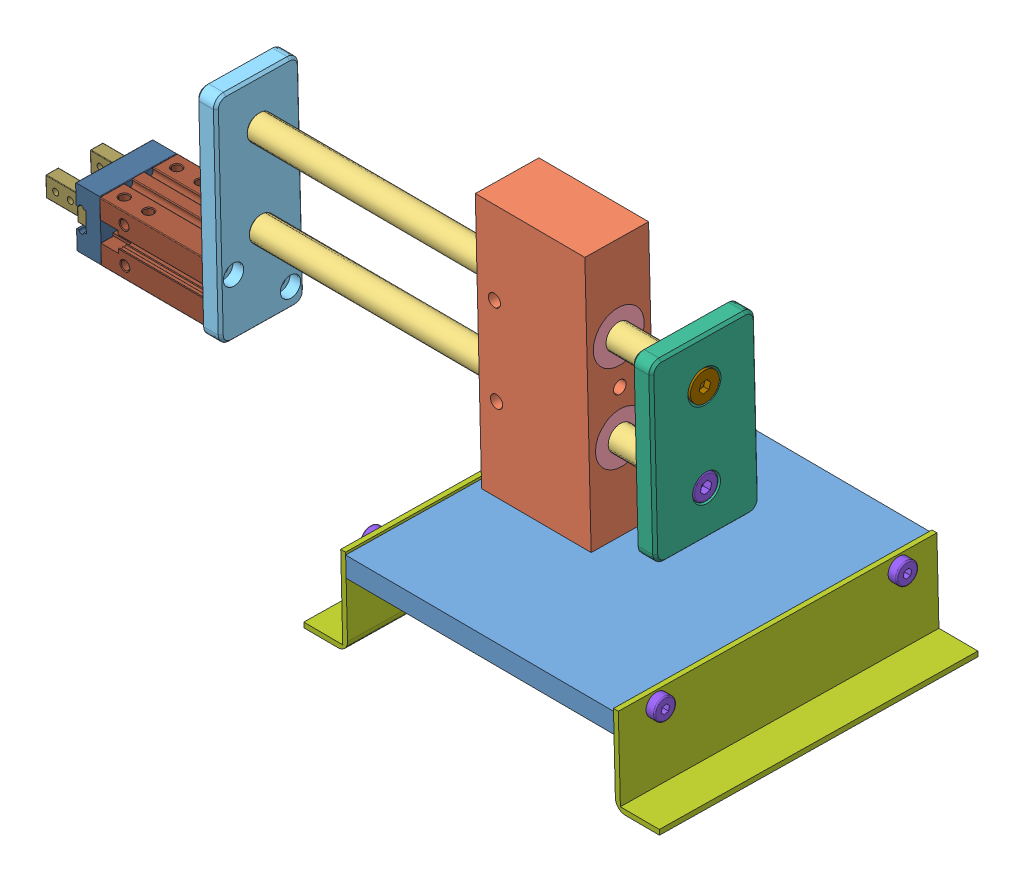
SolidWorks assembly cum s2, configuration Default. Lengths in mm.
Overall size (307.39 137.7 128.52).
27 component instances, 12 part files, 55 mates.
Components (placement in the parent):
- tam de lon-1: tam de lon [Default] at (119.0958 51.1975 54.0073) x (-0.999587 -0.017639 -0.022689) z (-0.022562 -0.007384 0.999718) size (110 8 125)
- con truot s1-2: con truot s1 [Default] at (88.5768 136.6703 53.9498) x (0.999587 0.017639 0.022689) z (0.022562 0.007384 -0.999718) size (45 102 25)
- chot dan huong-1: chot dan huong [Default] at (-36.4151 116.9624 50.9833) x (0.021471 -0.983136 -0.181614) z (-0.019103 -0.182026 0.983108) size (10 175 10)
- chot dan huong-2: chot dan huong [Default] at (-35.7921 81.9688 50.739) x (0.026236 -0.237789 -0.970963) z (0.011731 -0.971157 0.238153) size (10 175 10)
- bac lot-1: bac lot [Default] at (66.3976 118.7766 53.3171) x (0.028076 -0.767933 -0.639915) z (-0.006137 -0.640287 0.768111) size (20 12 20)
- bac lot-2: bac lot [Default] at (67.0207 83.783 53.0727) x (0.018145 -0.999587 -0.022287) z (-0.022287 -0.022689 0.999494) size (20 12 20)
- bac lot-3: bac lot [Default] at (111.379 119.5704 54.3381) x (-0.014484 -0.372719 0.927831) z (0.024823 -0.927776 -0.37231) size (20 12 20)
- bac lot-4: bac lot [Default] at (112.0021 84.5768 54.0937) x (-0.014484 -0.372719 0.927831) z (0.024823 -0.927776 -0.37231) size (20 12 20)
- ban canh truoc-1: ban canh truoc [Default] at (-35.9612 91.467 50.8053) x (-0.022562 -0.007384 0.999718) z (0.017801 -0.999817 -0.006983) size (33 8 86)
- ban canh sau -S1-1: ban canh sau -S1 [Default] at (138.8241 102.5524 54.8318) x (-0.022562 -0.007384 0.999718) z (-0.017801 0.999817 0.006983) size (41 8 70)
- khoi do-1: khoi do [Default] at (173.7917 36.5109 117.6508) x (0.022562 0.007384 -0.999718) z (-0.999587 -0.017639 -0.022689) size (125 35 18)
- khoi do-2: khoi do [Default] at (64.9414 35.4633 -9.8487) x (-0.022562 -0.007384 0.999718) z (0.999587 0.017639 0.022689) size (125 35 18)
- socket head thin cap screw_din-2: socket head thin cap screw_din [DIN 7984 - M5 x 12 --- 9.6N] at (57.6203 45.7804 100.0932) x (0.999587 0.017639 0.022689) z (-0.022689 -0.0002 0.999743) size (15.5 8.5 8.5)
- socket head thin cap screw_din-3: socket head thin cap screw_din [DIN 7984 - M5 x 12 --- 9.6N] at (59.7637 46.4818 5.12) x (0.999587 0.017639 0.022689) z (-0.022689 -0.0002 0.999743) size (15.5 8.5 8.5)
- socket head thin cap screw_din-4: socket head thin cap screw_din [DIN 7984 - M5 x 12 --- 9.6N] at (180.7137 48.6161 7.8654) x (-0.999587 -0.017639 -0.022689) z (0.022689 -0.968916 -0.246346) size (15.5 8.5 8.5)
- socket head thin cap screw_din-5: socket head thin cap screw_din [DIN 7984 - M5 x 12 --- 9.6N] at (178.5703 47.9147 102.8386) x (-0.999587 -0.017639 -0.022689) z (0.022689 -0.968916 -0.246346) size (15.5 8.5 8.5)
- socket head thin cap screw_din-6: socket head thin cap screw_din [DIN 7984 - M5 x 12 --- 9.6N] at (108.0343 45.1492 61.2151) x (-0.017801 0.999817 0.006983) z (-0.006983 -0.007108 0.99995) size (15.5 8.5 8.5)
- socket head thin cap screw_din-7: socket head thin cap screw_din [DIN 7984 - M5 x 12 --- 9.6N] at (72.3876 44.6249 45.4025) x (-0.017801 0.999817 0.006983) z (-0.006983 -0.007108 0.99995) size (15.5 8.5 8.5)
- socket head thin cap screw_din-9: socket head thin cap screw_din [DIN 7984 - M6 x 14 --- 11N] at (146.9324 85.1931 54.8866) x (-0.999587 -0.017639 -0.022689) z (0.022689 -0.968916 -0.246346) size (18 10 10)
- socket head thin cap screw_din-10: socket head thin cap screw_din [DIN 7984 - M6 x 14 --- 11N] at (-43.5888 81.8312 50.562) x (0.999587 0.017639 0.022689) z (-0.022689 -0.0002 0.999743) size (18 10 10)
- socket csink head cap screw 10642_din-2: socket csink head cap screw 10642_din [EN ISO 10642 - M6 x 16 - 16N] at (-44.6317 116.8174 50.7968) x (0.999587 0.017639 0.022689) z (-0.022678 -0.000819 0.999742) size (16 11.34 11.34)
- socket csink head cap screw 10642_din-3: socket csink head cap screw 10642_din [EN ISO 10642 - M6 x 16 - 16N] at (146.7292 120.1941 55.1405) x (-0.999587 -0.017639 -0.022689) z (0.021761 -0.980227 -0.196676) size (16 11.34 11.34)
- NMHZ2-16D-1: NMHZ2-16D [Default] at (-27.9266 61.2035 28.3499) x (-0.022562 -0.007384 0.999718) z (-0.999587 -0.017639 -0.022689) size (30.6 23.6 52.5)
  - NMHZ2-16D Slipway-1: NMHZ2-16D Slipway [Default] at (22.4069 2.6078 57.488) size (30.1 23.6 10)
  - NMHZ2-16D cylinder-2: NMHZ2-16D cylinder [Default] at (22.4069 2.6078 14.988) size (30.6 23.6 42.5)
- NMHZ2-16D air claw-1: NMHZ2-16D air claw [Default] at (-93.9561 62.4848 50.0193) x (-0.022562 -0.007384 0.999718) z (-0.999587 -0.017639 -0.022689) size (12 10 21)
- NMHZ2-16D air claw-2: NMHZ2-16D air claw [Default] at (-93.9006 62.503 47.5619) x (0.022562 0.007384 -0.999718) z (-0.999587 -0.017639 -0.022689) size (12 10 21)
Mates (geometry in assembly coordinates):
- Parallel5: parallel anti-aligned: plane of tam de lon-1 through (119.0958 51.1975 54.0073) normal (-0.017801 0.999817 0.006983); plane of con truot s1-2 through (90.1077 50.686 53.3493) normal (0.017801 -0.999817 -0.006983)
- Parallel6: parallel anti-aligned: plane of tam de lon-1 through (172.8053 43.7076 117.6817) normal (-0.022562 -0.007384 0.999718); plane of con truot s1-2 through (67.6142 66.3785 40.454) normal (0.022562 0.007384 -0.999718)
- Concentric3: concentric aligned: cylinder of tam de lon-1 through (72.2844 50.4239 45.443) axis (0.017801 -0.999817 -0.006983) radius 2.75; circle of con truot s1-2
- Coincident1: coincident anti-aligned: plane of tam de lon-1 through (119.0958 51.1975 54.0073) normal (-0.017801 0.999817 0.006983); plane of con truot s1-2 through (90.1077 50.686 53.3493) normal (0.017801 -0.999817 -0.006983)
- Concentric4: concentric anti-aligned: cylinder of con truot s1-2 through (41.408 118.3356 52.7498) axis (0.999587 0.017639 0.022689) radius 6; cylinder of chot dan huong-1 through (236.4721 121.7778 57.1775) axis (-0.999587 -0.017639 -0.022689) radius 5
- Concentric5: concentric anti-aligned: cylinder of con truot s1-2 through (42.031 83.342 52.5054) axis (0.999587 0.017639 0.022689) radius 6; cylinder of chot dan huong-2 through (237.0952 86.7842 56.9331) axis (-0.999587 -0.017639 -0.022689) radius 5
- Concentric6: concentric anti-aligned: cylinder of con truot s1-2 through (41.408 118.3356 52.7498) axis (0.999587 0.017639 0.022689) radius 6; cylinder of bac lot-1 through (78.3927 118.9883 53.5893) axis (-0.999587 -0.017639 -0.022689) radius 6
- Coincident2: coincident anti-aligned: plane of con truot s1-2 through (68.3968 118.8119 53.3624) normal (-0.999587 -0.017639 -0.022689); plane of bac lot-1 through (68.3968 118.8119 53.3624) normal (0.999587 0.017639 0.022689)
- Concentric7: concentric anti-aligned: cylinder of con truot s1-2 through (42.031 83.342 52.5054) axis (0.999587 0.017639 0.022689) radius 6; cylinder of bac lot-2 through (79.0157 83.9947 53.3449) axis (-0.999587 -0.017639 -0.022689) radius 6
- Coincident3: coincident anti-aligned: plane of con truot s1-2 through (69.0199 83.8183 53.1181) normal (-0.999587 -0.017639 -0.022689); plane of bac lot-2 through (69.0199 83.8183 53.1181) normal (0.999587 0.017639 0.022689)
- Concentric8: concentric aligned: cylinder of con truot s1-2 through (41.408 118.3356 52.7498) axis (0.999587 0.017639 0.022689) radius 6; cylinder of bac lot-3 through (99.384 119.3587 54.0658) axis (0.999587 0.017639 0.022689) radius 6
- Coincident4: coincident anti-aligned: plane of con truot s1-2 through (109.3799 119.5351 54.2927) normal (0.999587 0.017639 0.022689); plane of bac lot-3 through (109.3799 119.5351 54.2927) normal (-0.999587 -0.017639 -0.022689)
- Concentric9: concentric aligned: cylinder of con truot s1-2 through (42.031 83.342 52.5054) axis (0.999587 0.017639 0.022689) radius 6; cylinder of bac lot-4 through (100.0071 84.3651 53.8214) axis (0.999587 0.017639 0.022689) radius 6
- Coincident5: coincident anti-aligned: plane of con truot s1-2 through (110.0029 84.5415 54.0483) normal (0.999587 0.017639 0.022689); plane of bac lot-4 through (110.0029 84.5415 54.0483) normal (-0.999587 -0.017639 -0.022689)
- Concentric10: concentric aligned: cylinder of chot dan huong-1 through (236.4721 121.7778 57.1775) axis (-0.999587 -0.017639 -0.022689) radius 5; cylinder of ban canh truoc-1 through (-36.4151 116.9624 50.9833) axis (-0.999587 -0.017639 -0.022689) radius 3.3
- Concentric11: concentric aligned: cylinder of chot dan huong-2 through (237.0952 86.7842 56.9331) axis (-0.999587 -0.017639 -0.022689) radius 5; cylinder of ban canh truoc-1 through (-35.7921 81.9688 50.739) axis (-0.999587 -0.017639 -0.022689) radius 3.3
- Coincident6: coincident anti-aligned: plane of chot dan huong-1 through (-36.4151 116.9624 50.9833) normal (-0.999587 -0.017639 -0.022689); plane of ban canh truoc-1 through (-35.9612 91.467 50.8053) normal (0.999587 0.017639 0.022689)
- Coincident7: coincident anti-aligned: plane of chot dan huong-2 through (-35.7921 81.9688 50.739) normal (-0.999587 -0.017639 -0.022689); plane of ban canh truoc-1 through (-35.9612 91.467 50.8053) normal (0.999587 0.017639 0.022689)
- Concentric12: concentric anti-aligned: cylinder of chot dan huong-1 through (236.4721 121.7778 57.1775) axis (-0.999587 -0.017639 -0.022689) radius 5; cylinder of ban canh sau -S1-1 through (138.5126 120.0492 54.954) axis (0.999587 0.017639 0.022689) radius 3.3
- Concentric13: concentric anti-aligned: cylinder of chot dan huong-2 through (237.0952 86.7842 56.9331) axis (-0.999587 -0.017639 -0.022689) radius 5; cylinder of ban canh sau -S1-1 through (139.1356 85.0556 54.7096) axis (0.999587 0.017639 0.022689) radius 3.3
- Coincident8: coincident anti-aligned: plane of chot dan huong-1 through (138.5126 120.0492 54.954) normal (0.999587 0.017639 0.022689); plane of ban canh sau -S1-1 through (138.8241 102.5524 54.8318) normal (-0.999587 -0.017639 -0.022689)
- Coincident9: coincident anti-aligned: plane of chot dan huong-2 through (139.1356 85.0556 54.7096) normal (0.999587 0.017639 0.022689); plane of ban canh sau -S1-1 through (138.8241 102.5524 54.8318) normal (-0.999587 -0.017639 -0.022689)
- Parallel7: parallel aligned: plane of tam de lon-1 through (65.671 42.6903 -9.7789) normal (-0.999587 -0.017639 -0.022689); plane of khoi do-1 through (176.0884 18.6354 -7.4646) normal (-0.999587 -0.017639 -0.022689)
- Parallel8: parallel aligned: plane of tam de lon-1 through (119.0958 51.1975 54.0073) normal (-0.017801 0.999817 0.006983); plane of khoi do-1 through (175.4654 53.629 -7.2202) normal (-0.017801 0.999817 0.006983)
- Concentric14: concentric aligned: cylinder of tam de lon-1 through (160.2221 48.2545 7.4003) axis (0.999587 0.017639 0.022689) radius 2.5; cylinder of khoi do-1 through (52.2667 46.3495 4.9498) axis (0.999587 0.017639 0.022689) radius 2.5
- Coincident10: coincident anti-aligned: plane of tam de lon-1 through (175.6256 44.6306 -7.2831) normal (0.999587 0.017639 0.022689); plane of khoi do-1 through (176.0884 18.6354 -7.4646) normal (-0.999587 -0.017639 -0.022689)
- Parallel9: parallel anti-aligned: plane of tam de lon-1 through (65.671 42.6903 -9.7789) normal (-0.999587 -0.017639 -0.022689); plane of khoi do-2 through (63.3136 15.7721 115.0043) normal (0.999587 0.017639 0.022689)
- Parallel10: parallel anti-aligned: plane of tam de lon-1 through (119.0958 51.1975 54.0073) normal (-0.017801 0.999817 0.006983); plane of khoi do-2 through (63.3136 15.7721 115.0043) normal (0.017801 -0.999817 -0.006983)
- Concentric15: concentric aligned: cylinder of tam de lon-1 through (80.2552 46.8434 5.5851) axis (-0.999587 -0.017639 -0.022689) radius 2.5; cylinder of khoi do-2 through (188.2106 48.7484 8.0356) axis (-0.999587 -0.017639 -0.022689) radius 2.5
- Coincident11: coincident anti-aligned: plane of tam de lon-1 through (65.671 42.6903 -9.7789) normal (-0.999587 -0.017639 -0.022689); plane of khoi do-2 through (63.3136 15.7721 115.0043) normal (0.999587 0.017639 0.022689)
- Concentric16: concentric aligned: cylinder of khoi do-2 through (186.0672 48.047 103.0088) axis (-0.999587 -0.017639 -0.022689) radius 2.5; cylinder of socket head thin cap screw_din-2 through (25.8834 45.2204 99.3728) axis (-0.999587 -0.017639 -0.022689) radius 4.25
- Coincident12: coincident anti-aligned: plane of khoi do-2 through (61.2788 17.7365 114.9729) normal (-0.999587 -0.017639 -0.022689); plane of socket head thin cap screw_din-2 through (61.0438 50.0915 100.1718) normal (0.999587 0.017639 0.022689)
- Concentric17: concentric aligned: cylinder of khoi do-2 through (188.2106 48.7484 8.0356) axis (-0.999587 -0.017639 -0.022689) radius 2.5; cylinder of socket head thin cap screw_din-3 through (28.0268 45.9218 4.3996) axis (-0.999587 -0.017639 -0.022689) radius 4.25
- Coincident13: coincident anti-aligned: plane of khoi do-2 through (61.2788 17.7365 114.9729) normal (-0.999587 -0.017639 -0.022689); plane of socket head thin cap screw_din-3 through (63.1872 50.7929 5.1986) normal (0.999587 0.017639 0.022689)
- Concentric18: concentric aligned: cylinder of khoi do-1 through (52.2667 46.3495 4.9498) axis (0.999587 0.017639 0.022689) radius 2.5; cylinder of socket head thin cap screw_din-4 through (212.4506 49.1762 8.5858) axis (0.999587 0.017639 0.022689) radius 4.25
- Coincident14: coincident anti-aligned: plane of khoi do-1 through (178.052 20.6703 -7.4053) normal (0.999587 0.017639 0.022689); plane of socket head thin cap screw_din-4 through (177.2901 49.6031 3.6681) normal (-0.999587 -0.017639 -0.022689)
- Concentric19: concentric aligned: cylinder of khoi do-1 through (50.1234 45.6481 99.9231) axis (0.999587 0.017639 0.022689) radius 2.5; cylinder of socket head thin cap screw_din-5 through (210.3072 48.4747 103.559) axis (0.999587 0.017639 0.022689) radius 4.25
- Coincident15: coincident anti-aligned: plane of khoi do-1 through (178.052 20.6703 -7.4053) normal (0.999587 0.017639 0.022689); plane of socket head thin cap screw_din-5 through (175.1467 48.9017 98.6413) normal (-0.999587 -0.017639 -0.022689)
- Concentric20: concentric aligned: cylinder of tam de lon-1 through (107.972 48.6485 61.2395) axis (0.017801 -0.999817 -0.006983) radius 5; cylinder of socket head thin cap screw_din-6 through (108.5995 13.405 60.9934) axis (0.017801 -0.999817 -0.006983) radius 4.25
- Coincident16: coincident anti-aligned: plane of tam de lon-1 through (107.972 48.6485 61.2395) normal (0.017801 -0.999817 -0.006983); plane of socket head thin cap screw_din-6 through (103.7228 48.5731 61.2093) normal (-0.017801 0.999817 0.006983)
- Concentric21: concentric aligned: cylinder of tam de lon-1 through (72.2844 50.4239 45.443) axis (0.017801 -0.999817 -0.006983) radius 2.75; cylinder of socket head thin cap screw_din-7 through (72.9528 12.8807 45.1808) axis (0.017801 -0.999817 -0.006983) radius 4.25
- Coincident17: coincident anti-aligned: plane of tam de lon-1 through (72.3253 48.1243 45.4269) normal (0.017801 -0.999817 -0.006983); plane of socket head thin cap screw_din-7 through (68.0761 48.0489 45.3967) normal (-0.017801 0.999817 0.006983)
- Concentric22: concentric aligned: cylinder of ban canh sau -S1-1 through (142.9341 85.1226 54.7958) axis (0.999587 0.017639 0.022689) radius 5.5; cylinder of socket head thin cap screw_din-9 through (178.6693 85.7532 55.607) axis (0.999587 0.017639 0.022689) radius 5
- Coincident18: coincident anti-aligned: plane of ban canh sau -S1-1 through (142.9341 85.1226 54.7958) normal (0.999587 0.017639 0.022689); plane of socket head thin cap screw_din-9 through (143.0223 86.3564 49.9512) normal (-0.999587 -0.017639 -0.022689)
- Concentric23: concentric aligned: cylinder of ban canh truoc-1 through (-39.5905 81.9017 50.6527) axis (-0.999587 -0.017639 -0.022689) radius 5.5; cylinder of socket head thin cap screw_din-10 through (-75.3257 81.2711 49.8416) axis (-0.999587 -0.017639 -0.022689) radius 5
- Coincident19: coincident anti-aligned: plane of ban canh truoc-1 through (-39.5905 81.9017 50.6527) normal (-0.999587 -0.017639 -0.022689); plane of socket head thin cap screw_din-10 through (-39.6787 86.901 50.6517) normal (0.999587 0.017639 0.022689)
- Coincident20: coincident aligned: cone of ban canh truoc-1 through (-41.2131 116.8777 50.8744) axis (0.999587 0.017639 0.022689); cone of socket csink head cap screw 10642_din-2 through (-43.5822 116.8359 50.8207) axis (0.999587 0.017639 0.022689)
- Coincident21: coincident aligned: cone of ban canh sau -S1-1 through (143.3106 120.1338 55.0629) axis (-0.999587 -0.017639 -0.022689); cone of socket csink head cap screw 10642_din-3 through (145.6796 120.1756 55.1167) axis (-0.999587 -0.017639 -0.022689)
- Concentric24: concentric anti-aligned: cylinder of ban canh truoc-1 through (-35.848 71.0895 61.6604) axis (-0.999587 -0.017639 -0.022689) radius 2.25; cylinder of NMHZ2-16D-1/NMHZ2-16D cylinder-2 through (-58.8385 70.6838 61.1386) axis (0.999587 0.017639 0.022689) radius 2
- Concentric25: concentric aligned: cylinder of ban canh truoc-1 through (-39.4828 56.1771 39.4621) axis (0.999587 0.017639 0.022689) radius 4; cylinder of NMHZ2-16D-1/NMHZ2-16D cylinder-2 through (-58.0751 55.849 39.04) axis (0.999587 0.017639 0.022689) radius 2
- Coincident22: coincident anti-aligned: plane of ban canh truoc-1 through (-43.9579 91.3259 50.6238) normal (-0.999587 -0.017639 -0.022689); plane of NMHZ2-16D-1/NMHZ2-16D cylinder-2 through (-43.4603 63.381 50.4286) normal (0.999587 0.017639 0.022689)
- Parallel11: parallel anti-aligned: plane of NMHZ2-16D-1/NMHZ2-16D Slipway-1 through (-91.4326 62.6917 26.8345) normal (-0.999587 -0.017639 -0.022689); plane of NMHZ2-16D air claw-1 through (-92.2277 62.4315 62.0613) normal (0.999587 0.017639 0.022689)
- Concentric26: concentric anti-aligned: cylinder of NMHZ2-16D-1/NMHZ2-16D Slipway-1 through (-93.503 66.6557 26.8171) axis (-0.022562 -0.007384 0.999718) radius 1; cylinder of NMHZ2-16D air claw-1 through (-94.298 66.3955 62.0439) axis (0.022562 0.007384 -0.999718) radius 1
- Parallel12: parallel anti-aligned: plane of NMHZ2-16D-1/NMHZ2-16D Slipway-1 through (-91.4326 62.6917 26.8345) normal (-0.999587 -0.017639 -0.022689); plane of NMHZ2-16D air claw-2 through (-91.6307 62.6269 35.6107) normal (0.999587 0.017639 0.022689)
- Concentric27: concentric aligned: cylinder of NMHZ2-16D-1/NMHZ2-16D Slipway-1 through (-93.3606 58.6571 26.7612) axis (-0.022562 -0.007384 0.999718) radius 1; cylinder of NMHZ2-16D air claw-2 through (-93.5587 58.5923 35.5374) axis (-0.022562 -0.007384 0.999718) radius 1
